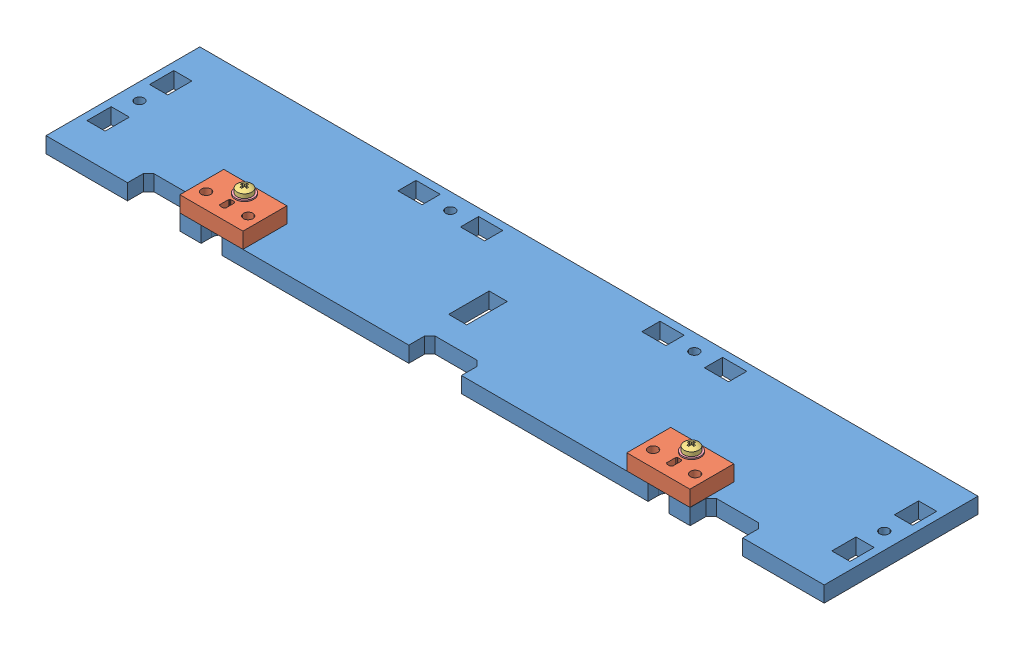
SolidWorks assembly Assembly Back, configuration Valor predeterminado. Lengths in mm.
Overall size (296 18.37 58.5).
13 component instances, 5 part files, 21 mates.
Components (placement in the parent):
- Back-1: Back [Valor predeterminado] at (-154.3442 0 -25.7118) x (0 0 1) z (0 1 0) size (58.5 296 6)
- Y-Smooth Rod Stop-1: Y-Smooth Rod Stop [Valor predeterminado] at (41.1385 12 34.4464) x (1 0 0) z (0 -1 0) size (24 16.7 6)
- Assembly Screw DIN 7985 - M3 x 16 --- 16N + Washer DIN 125A - M3-1: Assembly Screw DIN 7985 - M3 x 16 --- 16N + Washer DIN 125A - M3 [Valor predeterminado] at (85.8164 8.6091 27.6453) x (0 1 0) z (-0.038581 0 0.999255) size (18.37 7 7)
  - Screw DIN 7985 - M3 x 16 --- 16N-1: Screw DIN 7985 - M3 x 16 --- 16N [Valor predeterminado] at (6.2909 0.1077 18.3725) size (18.37 5.6 5.6)
  - Washer DIN 125A - M3-1: Washer DIN 125A - M3 [Valor predeterminado] at (3.3909 0.1077 18.3725) size (0.5 7 7)
- Assembly Screw DIN 7985 - M3 x 16 --- 16N + Washer DIN 125A - M3-3: Assembly Screw DIN 7985 - M3 x 16 --- 16N + Washer DIN 125A - M3 [Valor predeterminado] at (-84.1835 8.6091 27.6453) x (0 1 0) z (-0.038581 0 0.999255) size (18.37 7 7)
  - Screw DIN 7985 - M3 x 16 --- 16N-1: Screw DIN 7985 - M3 x 16 --- 16N [Valor predeterminado] at (6.2909 0.1077 18.3725) size (18.37 5.6 5.6)
  - Washer DIN 125A - M3-1: Washer DIN 125A - M3 [Valor predeterminado] at (3.3909 0.1077 18.3725) size (0.5 7 7)
- Y-Smooth Rod Stop-2: Y-Smooth Rod Stop [Valor predeterminado] at (-128.8614 12 34.4464) x (1 0 0) z (0 -1 0) size (24 16.7 6)
- Nut DIN 934 - M3-1: Nut DIN 934 - M3 [Valor predeterminado] at (-85 -1.7 46) x (0 1 0) z (0.89447 0 -0.447128) size (2.4 5.5 6.35)
- Washer DIN 125A - M3-1: Washer DIN 125A - M3 [Valor predeterminado] at (-85 -0.5 46) x (0 1 0) z (0.998989 0 0.044946) size (0.5 7 7)
- Nut DIN 934 - M3-2: Nut DIN 934 - M3 [Valor predeterminado] at (85 -1.7 46) x (0 1 0) z (0.895045 0 -0.445976) size (2.4 5.5 6.35)
- Washer DIN 125A - M3-2: Washer DIN 125A - M3 [Valor predeterminado] at (85 -0.5 46) x (0 1 0) z (0.998989 0 0.044946) size (0.5 7 7)
Mates (geometry in assembly coordinates):
- Coincidente1: coincident: plane of assembly through (0 0 0) normal (0 1 0); plane of Back-1 through (-154.3442 0 -25.7118) normal (0 -1 0); plane of assembly
- Coincidente2: coincident: plane of assembly through (0 0 0) normal (0 0 1); plane of Back-1 through (-154.3442 6 0) normal (0 0 -1); plane of assembly
- Simétrico1: symmetric: plane of assembly; plane of assembly; plane of Back-1 through (148 6 -25.7118) normal (1 0 0); plane of Back-1 through (-148 6 -25.7118) normal (-1 0 0); plane of assembly
- Concêntrico1: concentric: cylinder of assembly; cylinder of assembly; cylinder of Back-1 through (85 6 46) axis (0 -1 0) radius 1.8; cylinder of Y-Smooth Rod Stop-1 through (85 6 46) axis (0 1 0) radius 1.8
- Coincidente3: coincident: plane of assembly; plane of assembly; plane of Back-1 through (-154.3442 6 -25.7118) normal (0 1 0); plane of Y-Smooth Rod Stop-1 through (41.1385 6 34.4464) normal (0 -1 0)
- Paralelo1: parallel: plane of assembly; plane of assembly; plane of Back-1 through (-154.3442 6 58.5) normal (0 0 1); plane of Y-Smooth Rod Stop-1 through (41.1385 6 58.5) normal (0 0 1)
- Concêntrico2: concentric: cylinder of assembly; cylinder of assembly; cylinder of Y-Smooth Rod Stop-1 through (85 6 46) axis (0 1 0) radius 1.8; cylinder of Assembly Screw DIN 7985 - M3 x 16 --- 16N + Washer DIN 125A - M3-1/Screw DIN 7985 - M3 x 16 --- 16N-1 through (85 14.9 46) axis (0 1 0) radius 1.5
- Coincidente5: coincident: plane of Y-Smooth Rod Stop-1 through (41.1385 12 34.4464) normal (0 1 0); plane of Assembly Screw DIN 7985 - M3 x 16 --- 16N + Washer DIN 125A - M3-1/Washer DIN 125A - M3-1 through (85 12 46) normal (0 -1 0)
- Coincidente7: coincident: plane of Assembly Screw DIN 7985 - M3 x 16 --- 16N + Washer DIN 125A - M3-3/Washer DIN 125A - M3-1 through (-85 12 46) normal (0 -1 0); plane of Y-Smooth Rod Stop-2 through (-128.8614 12 34.4464) normal (0 1 0)
- Concêntrico4: concentric: cylinder of assembly; cylinder of assembly; cylinder of Assembly Screw DIN 7985 - M3 x 16 --- 16N + Washer DIN 125A - M3-3/Screw DIN 7985 - M3 x 16 --- 16N-1 through (-85 14.9 46) axis (0 1 0) radius 1.5; cylinder of Y-Smooth Rod Stop-2 through (-85 6 46) axis (0 1 0) radius 1.8
- Coincidente8: coincident: plane of assembly; plane of assembly; plane of Back-1 through (-154.3442 6 -25.7118) normal (0 1 0); plane of Y-Smooth Rod Stop-2 through (-128.8614 6 34.4464) normal (0 -1 0)
- Concêntrico5: concentric: cylinder of assembly; cylinder of assembly; cylinder of Back-1 through (-85 6 46) axis (0 -1 0) radius 1.8; cylinder of Assembly Screw DIN 7985 - M3 x 16 --- 16N + Washer DIN 125A - M3-3/Screw DIN 7985 - M3 x 16 --- 16N-1 through (-85 14.9 46) axis (0 1 0) radius 1.5
- Paralelo2: parallel: plane of assembly; plane of assembly; plane of Back-1 through (-154.3442 6 58.5) normal (0 0 1); plane of Y-Smooth Rod Stop-2 through (-128.8614 6 58.5) normal (0 0 1)
- Concêntrico6: concentric: cylinder of assembly; cylinder of assembly; cylinder of Assembly Screw DIN 7985 - M3 x 16 --- 16N + Washer DIN 125A - M3-3/Screw DIN 7985 - M3 x 16 --- 16N-1 through (-85 14.9 46) axis (0 1 0) radius 1.5; cylinder of Washer DIN 125A - M3-1 through (-85 0 46) axis (0 -1 0) radius 1.6
- Coincidente10: coincident: plane of assembly; plane of assembly; plane of Back-1 through (-154.3442 0 -25.7118) normal (0 -1 0); plane of Washer DIN 125A - M3-1 through (-85 0 46) normal (0 1 0)
- Concêntrico7: concentric: cylinder of assembly; cylinder of assembly; cylinder of Assembly Screw DIN 7985 - M3 x 16 --- 16N + Washer DIN 125A - M3-3/Screw DIN 7985 - M3 x 16 --- 16N-1 through (-85 14.9 46) axis (0 1 0) radius 1.5; cylinder of Nut DIN 934 - M3-1 through (-85 -0.5 46) axis (0 -1 0) radius 1.25
- Coincidente11: coincident: plane of assembly; plane of assembly; plane of Nut DIN 934 - M3-1 through (-87.6497 -0.5 44.2501) normal (0 1 0); plane of Washer DIN 125A - M3-1 through (-85 -0.5 46) normal (0 -1 0)
- Coincidente12: coincident: plane of assembly; plane of assembly; plane of Nut DIN 934 - M3-2 through (82.3525 -0.5 44.2467) normal (0 1 0); plane of Washer DIN 125A - M3-2 through (85 -0.5 46) normal (0 -1 0)
- Concêntrico9: concentric: cylinder of assembly; cylinder of assembly; cylinder of Assembly Screw DIN 7985 - M3 x 16 --- 16N + Washer DIN 125A - M3-1/Screw DIN 7985 - M3 x 16 --- 16N-1 through (85 14.9 46) axis (0 1 0) radius 1.5; cylinder of Washer DIN 125A - M3-2 through (85 0 46) axis (0 -1 0) radius 1.6
- Coincidente13: coincident: plane of assembly; plane of assembly; plane of Back-1 through (-154.3442 0 -25.7118) normal (0 -1 0); plane of Washer DIN 125A - M3-2 through (85 0 46) normal (0 1 0)
- Concêntrico10: concentric: cylinder of assembly; cylinder of assembly; cylinder of Assembly Screw DIN 7985 - M3 x 16 --- 16N + Washer DIN 125A - M3-1/Screw DIN 7985 - M3 x 16 --- 16N-1 through (85 14.9 46) axis (0 1 0) radius 1.5; cylinder of Nut DIN 934 - M3-2 through (85 -0.5 46) axis (0 -1 0) radius 1.25
